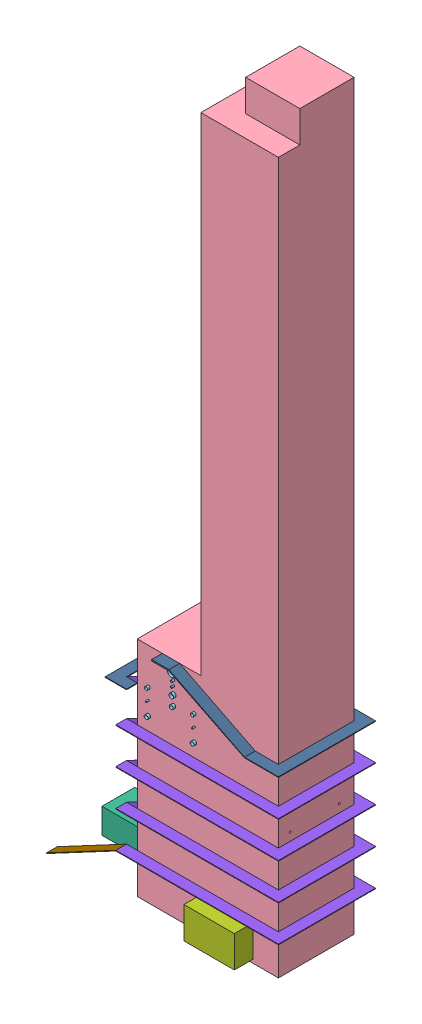
SolidWorks assembly COOL BOX, configuration Default. Lengths in mm.
Overall size (19295.12 58890 8350).
37 component instances, 13 part files, 49 mates.
Components (placement in the parent):
- Platforma 1-1: Platforma 1 [Default] x (-1 0 0) z (0 1 0) size (10900 5700 300)
- Platforma 1-2: Platforma 1 [Default] at (0 2875 0) x (-1 0 0) z (0 1 0) size (10900 5700 300)
- Platforma 1-3: Platforma 1 [Default] at (0 5750 0) x (-1 0 0) z (0 1 0) size (10900 5700 300)
- Platforma 1-4: Platforma 1 [Default] at (0 8625 0) x (-1 0 0) z (0 1 0) size (10900 5700 300)
- Platforma 1-5: Platforma 1 [Default] at (0 11500 0) x (-1 0 0) z (0 1 0) size (10900 5700 300)
- Platforma 1-6: Platforma 1 [Default] at (0 14375 0) x (-1 0 0) z (0 1 0) size (10900 5700 300)
- Platforma 1-7: Platforma 1 [Default] at (0 17250 0) x (-1 0 0) z (0 1 0) size (10900 5700 300)
- Part1^COOL BOX-1: Part1^COOL BOX [Default] at origin size (5850 100 5700)
- Part1^COOL BOX-2: Part1^COOL BOX [Default] at (0 2875 0) size (5850 100 5700)
- Part1^COOL BOX-3: Part1^COOL BOX [Default] at (0 5750 0) size (5850 100 5700)
- Part1^COOL BOX-4: Part1^COOL BOX [Default] at (0 8625 0) size (5850 100 5700)
- Part1^COOL BOX-5: Part1^COOL BOX [Default] at (0 11500 0) size (5850 100 5700)
- Part1^COOL BOX-6: Part1^COOL BOX [Default] at (0 14375 0) size (5850 100 5700)
- Part1^COOL BOX-7: Part1^COOL BOX [Default] at (0 17250 0) size (5850 100 5700)
- Part1^COOL BOX-8: Part1^COOL BOX [Default] at (0 20125 0) size (5850 100 5700)
- Part1^COOL BOX-9: Part1^COOL BOX [Default] at (0 23000 0) size (5850 100 5700)
- Part1^COOL BOX-10: Part1^COOL BOX [Default] at (0 25875 0) size (5850 100 5700)
- Part1^COOL BOX-11: Part1^COOL BOX [Default] at (0 28335 0) size (5850 100 5700)
- Part1^COOL BOX-12: Part1^COOL BOX [Default] at (0 30795 0) size (5850 100 5700)
- Part1^COOL BOX-13: Part1^COOL BOX [Default] at (0 33255 0) size (5850 100 5700)
- Part1^COOL BOX-14: Part1^COOL BOX [Default] at (0 35715 0) size (5850 100 5700)
- Part2^COOL BOX-1: Part2^COOL BOX [Default] at (0 58640 0) x (-1 0 0) z (0 1 0) size (4000 4000 100) (virtual)
- OPLATA 2-1: OPLATA 2 [Default] x (1 0 0) z (0 -1 0) size (11200 6000 58890)
- PRIKLJUCCI-1: PRIKLJUCCI [Default] at (0 0 5850) x (-1 0 0) z (0 0 1) size (3958 4520.04 200)
- EXPANSION TURBINE-2: EXPANSION TURBINE [Default] at (-150 200 -21.5065) x (0 -1 0) z (-1 0 0) size (2000 2600 3700)
- Part4^COOL BOX-2: Part4^COOL BOX [Default] at (0 0 5850) x (-1 0 0) z (0 0 1) size (4000 2500 1500)
- Stepeniste-1-1: Stepeniste-1 [Default] at (0 3175 0) x (-1 0 0) z (0 1 0) size (12900 7700 2925)
- Stepeniste-1-2: Stepeniste-1 [Default] at (0 6050 0) x (-1 0 0) z (0 1 0) size (12900 7700 2925)
- Stepeniste-1-3: Stepeniste-1 [Default] at (0 8925 0) x (-1 0 0) z (0 1 0) size (12900 7700 2925)
- Stepeniste-1-4: Stepeniste-1 [Default] at (0 11800 0) x (-1 0 0) z (0 1 0) size (12900 7700 2925)
- POCETAK STEPENISTA-3: POCETAK STEPENISTA [Default] at (0 3175 6700) size (5499.45 2975 850)
- Part5^COOL BOX-1: Part5^COOL BOX [Default] at (0 14675 0) x (-1 0 0) z (0 1 0) size (13750 7700 3075)
- TEMELJNA OSNOVA-1: TEMELJNA OSNOVA [Default] at origin size (10870 10000 5200) (virtual)
- Part3^COOL BOX-1: Part3^COOL BOX [Default] at (0 6050 0) x (-1 0 0) z (0 1 0) size (1032.48 112.79 100)
- Part3^COOL BOX-3: Part3^COOL BOX [Default] at (0 8925 0) x (-1 0 0) z (0 1 0) size (1032.48 112.79 100)
- Part7^COOL BOX-1: Part7^COOL BOX [Default] at (0 6050 0) x (-1 0 0) z (0 1 0) size (673.77 153.19 100) (virtual)
- Part7^COOL BOX-2: Part7^COOL BOX [Default] at (0 8925 0) x (-1 0 0) z (0 1 0) size (673.77 153.19 100) (virtual)
Mates (geometry in assembly coordinates):
- InPlace1: in place: plane of Platforma 1-1 through (0 0 0) normal (0 1 0); moOrthogonalPlaneRef_w of Platforma 1-1; line of Platforma 1-1 through (55 -55 0) axis (0 0 -1); unknown of Platforma 1-1
- Coincident1: coincident aligned: plane of Platforma 1-1; plane of assembly
- Coincident2: coincident aligned: plane of Platforma 1-1; moOrthogonalPlaneRef_w of assembly
- Coincident3: coincident anti-aligned: plane of Platforma 1-1; moOrthogonalPlaneRef_w of assembly
- InPlace2: in place: plane of ? through (0 58440 0) normal (0 1 0); unknown of ?; line of ? through (-55 0 58440) axis (0 -1 0); unknown of Part2^COOL BOX-1
- Coincident1: coincident aligned: plane of Part2^COOL BOX-1; plane of assembly
- Coincident2: coincident aligned: plane of Part2^COOL BOX-1; moOrthogonalPlaneRef_w of assembly
- Coincident3: coincident anti-aligned: plane of Part2^COOL BOX-1; moOrthogonalPlaneRef_w of assembly
- InPlace3: in place: line of Platforma 1-1 through (0 0 5700) axis (0 -1 0); plane of OPLATA 2-1 through (0 0 0) normal (0 -1 0); line of Platforma 1-1 through (0 0 5700) axis (0 -1 0); plane of OPLATA 2-1 through (0 0 0) normal (0 0 1); line of Platforma 1-1 through (0 0 5700) axis (0 -1 0); line of OPLATA 2-1 through (55 -55 0) axis (0 0 1); plane of Platforma 1-1 through (0 0 5700) normal (0 -1 0); unknown of OPLATA 2-1
- Coincident4: coincident aligned: plane of Platforma 1-1; plane of OPLATA 2-1
- Coincident5: coincident aligned: moOrthogonalPlaneRef_w of Platforma 1-1 through (0 0 0) axis (0 0 1); plane of OPLATA 2-1 through (0 0 0) normal (0 0 1)
- Coincident6: coincident anti-aligned: moOrthogonalPlaneRef_w of Platforma 1-1 through (0 0 0) axis (-1 0 0); plane of OPLATA 2-1
- InPlace4: in place: line of OPLATA 2-1 through (11050 30355.9041 5850) axis (0 0 1); plane of ? through (0 0 5850) normal (0 0 1); line of OPLATA 2-1 through (11050 30355.9041 5850) axis (0 0 1); plane of ? through (0 0 5850) normal (0 1 0); line of OPLATA 2-1 through (11050 30355.9041 5850) axis (0 0 1); plane of ? through (0 0 5850) normal (1 0 0); plane of OPLATA 2-1 through (11050 30555.9041 5850) normal (0 0 1); unknown of ?
- Coincident7: coincident aligned: plane of OPLATA 2-1; plane of PRIKLJUCCI-1
- Coincident8: coincident aligned: moOrthogonalPlaneRef_w of OPLATA 2-1 through (0 0 5850) axis (0 -1 0); plane of PRIKLJUCCI-1
- Coincident9: coincident anti-aligned: moOrthogonalPlaneRef_w of OPLATA 2-1 through (0 0 5850) axis (1 0 0); plane of PRIKLJUCCI-1
- InPlace6: in place: line of OPLATA 2-1 through (11050 30355.9041 5850) axis (0 0 1); plane of ? through (0 0 5850) normal (0 0 1); line of OPLATA 2-1 through (11050 30355.9041 5850) axis (0 0 1); plane of ? through (0 0 5850) normal (0 1 0); line of OPLATA 2-1 through (11050 30355.9041 5850) axis (0 0 1); plane of ? through (0 0 5850) normal (1 0 0); plane of OPLATA 2-1 through (11050 30555.9041 5850) normal (0 0 1); unknown of ?
- Coincident4: coincident aligned: plane of OPLATA 2-1; plane of Part4^COOL BOX-2
- Coincident5: coincident aligned: moOrthogonalPlaneRef_w of OPLATA 2-1 through (0 0 5850) axis (0 -1 0); plane of Part4^COOL BOX-2
- Coincident6: coincident anti-aligned: moOrthogonalPlaneRef_w of OPLATA 2-1 through (0 0 5850) axis (1 0 0); plane of Part4^COOL BOX-2
- Coincident1: coincident aligned: plane of Stepeniste-1-1 through (-1000 3175 5850) normal (0 1 0); plane of Platforma 1-2 through (0 3175 5700) normal (0 1 0)
- Coincident2: coincident: plane of OPLATA 2-1 through (11050 30555.9041 -150) normal (1 0 0); line of Stepeniste-1-1 through (11050 3175 -150) axis (0 0 1)
- Coincident3: coincident: plane of OPLATA 2-1 through (11050 30555.9041 5850) normal (0 0 1); line of Stepeniste-1-1 through (11050 3175 5850) axis (-1 0 0)
- InPlace7: in place: line of ? through (-1000 2925 6700) axis (0 0 1); plane of ? through (0 0 6700) normal (0 0 1); line of ? through (-1000 2925 6700) axis (0 0 1); plane of ? through (0 0 6700) normal (0 1 0); line of ? through (-1000 2925 6700) axis (0 0 1); plane of ? through (0 0 6700) normal (1 0 0); plane of Stepeniste-1-1 through (-1000 3125 6700) normal (0 0 1); unknown of POCETAK STEPENISTA-3
- Coincident4: coincident aligned: plane of Stepeniste-1-1; plane of POCETAK STEPENISTA-3
- Coincident5: coincident aligned: moOrthogonalPlaneRef_w of Stepeniste-1-1 through (0 3175 6700) axis (0 1 0); plane of POCETAK STEPENISTA-3 through (0 3175 6700) normal (0 1 0)
- Coincident6: coincident anti-aligned: moOrthogonalPlaneRef_w of Stepeniste-1-1 through (0 3175 6700) axis (-1 0 0); plane of POCETAK STEPENISTA-3 through (0 3175 6700) normal (1 0 0)
- InPlace8: in place: line of Platforma 1-6 through (0 14475 5700) axis (0 1 0); plane of ? through (0 14475 0) normal (0 1 0); line of Platforma 1-6 through (0 14475 5700) axis (0 1 0); unknown of ?; line of Platforma 1-6 through (0 14475 5700) axis (0 1 0); line of ? through (-55 0 14475) axis (0 -1 0); plane of Platforma 1-6 through (0 14675 5700) normal (0 1 0); unknown of Part5^COOL BOX-1
- Coincident7: coincident aligned: plane of Platforma 1-6; plane of Part5^COOL BOX-1
- Coincident8: coincident aligned: moOrthogonalPlaneRef_w of Platforma 1-6 through (0 14675 0) axis (0 0 1); plane of Part5^COOL BOX-1
- Coincident9: coincident anti-aligned: moOrthogonalPlaneRef_w of Platforma 1-6 through (-1000 0 14675) axis (0 1 0); plane of Part5^COOL BOX-1
- Distance2: distance = 2100 mm aligned: plane of EXPANSION TURBINE-2 through (-3650 2100 5150) normal (0 -1 0); plane of Platforma 1-1 through (0 0 5700) normal (0 -1 0)
- Distance3: distance = 700 mm aligned: plane of EXPANSION TURBINE-2 through (-3650 4100 5150) normal (0 0 1); plane of OPLATA 2-1 through (11050 30555.9041 5850) normal (0 0 1)
- Coincident6: coincident anti-aligned: plane of OPLATA 2-1 through (-150 30555.9041 5850) normal (-1 0 0); plane of EXPANSION TURBINE-2 through (-150 4100 2550) normal (1 0 0)
- InPlace9: in place: plane of ? through (-1000 6050 5850) normal (0 1 0); plane of ? through (0 6050 0) normal (0 1 0); plane of ? through (-1000 6050 5850) normal (0 1 0); unknown of ?; plane of ? through (-1000 6050 5850) normal (0 1 0); unknown of ?; plane of ? through (0 6050 0) normal (0 1 0); unknown of ?
- Coincident7: coincident aligned: plane of Part3^COOL BOX-1; plane of Stepeniste-1-2
- Coincident8: coincident aligned: plane of Part3^COOL BOX-1; moOrthogonalPlaneRef_w of Stepeniste-1-2 through (0 6050 0) normal (0 0 1)
- Coincident9: coincident anti-aligned: plane of Part3^COOL BOX-1; moOrthogonalPlaneRef_w of Stepeniste-1-2 through (0 6050 0) normal (1 0 0)
- InPlace11: in place: plane of ? through (-1000 6050 5850) normal (0 1 0); plane of ? through (0 6050 0) normal (0 1 0); plane of ? through (-1000 6050 5850) normal (0 1 0); unknown of ?; plane of ? through (-1000 6050 5850) normal (0 1 0); unknown of ?; plane of ? through (0 6050 0) normal (0 1 0); unknown of ?
- Coincident13: coincident aligned: plane of Part7^COOL BOX-1; plane of Stepeniste-1-2
- Coincident14: coincident aligned: plane of Part7^COOL BOX-1; moOrthogonalPlaneRef_w of Stepeniste-1-2 through (0 6050 0) normal (0 0 1)
- Coincident15: coincident anti-aligned: unknown of ?; plane of ? through (0 6050 0) normal (1 0 0)
- PLANE1: unknown: plane of Platforma 1-7 through (0 17550 5700) normal (0 1 0); unknown of Platforma 1-7; unknown of Platforma 1-7
- LocalLPattern2: unknown: line of ? through (5050 20525 0) axis (0 -1 0)
- LocalLPattern3: unknown: line of Part1^COOL BOX-10 through (5050 46400 5700) axis (0 -1 0)
- PLANE3: unknown: plane of Part1^COOL BOX-14 through (10900 56240 0) normal (0 1 0); unknown of Part1^COOL BOX-14; unknown of Platforma 1-1; unknown of Platforma 1-1; unknown of Platforma 1-1; unknown of Platforma 1-1; unknown of Platforma 1-1; unknown of Platforma 1-7; unknown of Part1^COOL BOX-14; unknown of Part1^COOL BOX-14; unknown of Part1^COOL BOX-14; unknown of Part1^COOL BOX-14; unknown of Part1^COOL BOX-14; unknown of Part1^COOL BOX-14; unknown of Part2^COOL BOX-1; unknown of Part2^COOL BOX-1; unknown of Part2^COOL BOX-1; unknown of Part2^COOL BOX-1; unknown of Part2^COOL BOX-1; unknown of Part2^COOL BOX-1; unknown of Platforma 1-5; unknown of OPLATA 2-1; unknown of OPLATA 2-1; unknown of OPLATA 2-1; unknown of OPLATA 2-1; unknown of Platforma 1-1; unknown of OPLATA 2-1
- LocalLPattern4: unknown: line of OPLATA 2-1 through (-150 17700 5850) axis (0 -1 0); unknown of Stepeniste-1-1; unknown of Stepeniste-1-1; unknown of Stepeniste-1-4; unknown of OPLATA 2-1; unknown of Stepeniste-1-4; unknown of EXPANSION TURBINE-2; unknown of POCETAK STEPENISTA-3; unknown of Stepeniste-1-4; unknown of OPLATA 2-1; unknown of OPLATA 2-1; unknown of OPLATA 2-1; unknown of EXPANSION TURBINE-2; unknown of Stepeniste-1-4; unknown of OPLATA 2-1; unknown of Stepeniste-1-4; unknown of Stepeniste-1-4; unknown of OPLATA 2-1; sketch_entity of Platforma 1-1
- LocalLPattern6: unknown: line of OPLATA 2-1 through (11050 58890 -150) axis (0 -1 0)
- LocalLPattern8: unknown: line of OPLATA 2-1 through (11050 58890 -150) axis (0 -1 0)
